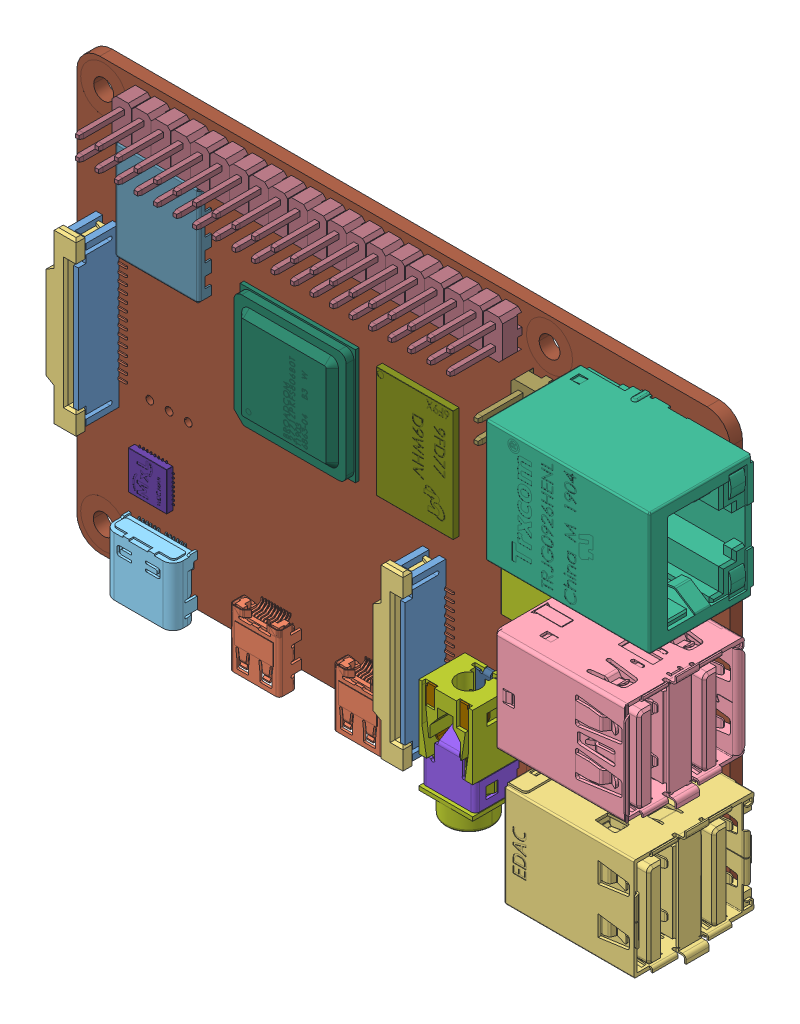
SolidWorks assembly Assembly Raspberry Pi 4 Model B step, configuration Default. Lengths in mm.
Overall size (89.07 58.45 20.84).
34 component instances, 25 part files, 0 mates.
Components (placement in the parent):
- Assembly Raspberry Pi 4 Model B step.STEP-1: Assembly Raspberry Pi 4 Model B step.STEP [Default] at origin size (89.07 58.45 20.84)
  - Display connector assembly.STEP-1: Display connector assembly.STEP [Default] at (-175.8005 -4.9769 88.3803) x (0 1 0) z (1 0 0) size (22.4 5.68 5.12)
    - 2.2 part 2 with combine.STEP-1: 2.2 part 2 with combine.STEP [Default] at (1.8587 0.0697 19.1) size (20.6 5.3 3)
    - 1.1 part 1 metal pin.STEP-1: 1.1 part 1 metal pin.STEP [Default] at (-5.0213 -2.5803 20.6021) x (0 0 1) z (-1 0 0) size (4.82 4.69 14.25)
    - 3.3 plastic.STEP-1: 3.3 plastic.STEP [Default] at (1.8587 1.7197 20.05) x (-1 0 0) z (0 1 0) size (22.4 3.9 5.18)
  - Display connector assembly-1.STEP-1: Display connector assembly-1.STEP [Default] at (-133.2905 -21.4369 88.3803) x (0 1 0) z (1 0 0) size (22.4 5.68 5.12)
    - 2.2 part 2 with combine.STEP-1: 2.2 part 2 with combine.STEP [Default] at (1.8587 0.0697 19.1) size (20.6 5.3 3)
    - 1.1 part 1 metal pin.STEP-1: 1.1 part 1 metal pin.STEP [Default] at (-5.0213 -2.5803 20.6021) x (0 0 1) z (-1 0 0) size (4.82 4.69 14.25)
    - 3.3 plastic.STEP-1: 3.3 plastic.STEP [Default] at (1.8587 1.7197 20.05) x (-1 0 0) z (0 1 0) size (22.4 3.9 5.18)
  - Card slot assembly.STEP-1: Card slot assembly.STEP [Default] at (-161.3453 3.4611 71.49) x (0 1 0) z (0 0 1) size (11.95 11.4 1.48)
    - card slot part 2 metal pin.STEP-1: card slot part 2 metal pin.STEP [Default] at (-3.5293 -7.6678 12.2938) x (0 -1 0) z (1 0 0) size (7.95 0.89 8.04)
    - sd card slot v1.STEP-1: sd card slot v1.STEP [Default] at (-18.1743 -9.7848 12.71) x (-1 0 0) z (0 0 -1) size (11.71 10.28 1.3)
    - part 3 v1.STEP-1: part 3 v1.STEP [Default] at (-6.4643 -9.3448 11.38) x (1 0 0) z (0 0 -1) size (11.95 11.4 1.45)
  - Microphone plug assembly.STEP-1: Microphone plug assembly.STEP [Default] at (-98.1635 -39.0194 79.6496) x (-1 0 0) z (0 1 0) size (7.23 7.55 15)
    - part 4 microphone plug.STEP-1: part 4 microphone plug.STEP [Default] at (7.027 9.1504 5.4512) size (7 6.8 15)
    - Microphone plug part 1.STEP-1: Microphone plug part 1.STEP [Default] at (7.027 11.4504 8.5512) x (-1 0 0) z (0 1 0) size (7.23 9.23 7.2)
    - part 2 microphon plug metal.STEP-1: part 2 microphon plug metal.STEP [Default] at (5.712 4.6004 12.1798) x (-1 0 0) z (0 1 0) size (6.87 8.22 7.3)
    - part 3 microphone plug.STEP-1: part 3 microphone plug.STEP [Default] at (7.042 6.6004 17.8712) x (-1 0 0) z (0 1 0) size (3.2 10.71 4.14)
  - 1.0 Plate raspberry Pi 4.STEP-1: 1.0 Plate raspberry Pi 4.STEP [Default] at (-116.6905 -3.1182 84.2) size (85 56 1.7)
  - 2.0. PIN HEADER  one.STEP-1: 2.0. PIN HEADER  one.STEP [Default] at (-97.6861 15.3918 88.3) size (5.08 5.08 11.8)
  - 3.0 PIN HEADER 20.STEP-1: 3.0 PIN HEADER 20.STEP [Default] at (-103.8305 21.3818 88.3) x (0 -1 0) z (0 0 1) size (5.08 50.8 11.8)
  - 4.0 metal plate..STEP-1: 4.0 metal plate..STEP [Default] at (-147.1905 11.3818 87.2) x (-1 0 0) z (0 0 1) size (11.01 13.01 1.6)
  - 5.0 CPU Broadcom.STEP-1: 5.0 CPU Broadcom.STEP [Default] at (-129.9505 1.4218 85.8) size (15 15 2.3)
  - 6.0 9FD77 D9WHV.STEP-1: 6.0 9FD77 D9WHV.STEP [Default] at (-114.4505 1.4218 85.8) size (10 14.5 0.8)
  - 7.0 MxL.STEP-1: 7.0 MxL.STEP [Default] at (-149.2005 -19.0782 85.8) size (5.48 5.48 0.9)
  - 8.0 Gigabit Ethernet Transceiver.STEP-1: 8.0 Gigabit Ethernet Transceiver.STEP [Default] at (-100.2005 6.9218 85.8) size (6.9 6.9 1.1)
  - 9.0 VLI PCIe USB 3.0 Controller.STEP-1: 9.0 VLI PCIe USB 3.0 Controller.STEP [Default] at (-99.2005 -7.0782 85.8) x (0 1 0) z (0 0 1) size (8.9 8.9 0.9)
  - 11.0 Female micro HDMI connector.STEP-1: 11.0 Female micro HDMI connector.STEP [Default] at (-133.2005 -25.4082 87.25) x (1 0 0) z (0 -1 0) size (6.5 3.51 7.5)
  - 11.0 Female micro HDMI connector.STEP-2: 11.0 Female micro HDMI connector.STEP [Default] at (-119.7005 -25.4082 87.25) x (1 0 0) z (0 -1 0) size (6.5 3.51 7.5)
  - 15.0   2x USB 2.0 PORT.STEP-1: 15.0   2x USB 2.0 PORT.STEP [Default] at (-87.9805 -22.0582 93.6) x (0 0 1) z (1 0 0) size (19.16 15.33 17.86)
  - 14.0  2x USB 3.0 PORT.STEP-1: 14.0  2x USB 3.0 PORT.STEP [Default] at (-88.0505 -4.0182 94.78) x (0 0 1) z (1 0 0) size (20.65 15.33 17.87)
  - 10.0 Female USB connector.STEP-1: 10.0 Female USB connector.STEP [Default] at (-147.9905 -24.6982 87.38) x (1 0 0) z (0 -1 0) size (8.94 3.96 7.9)
  - 12.0 Gigabit ethernet port raspberry.STEP-1: 12.0 Gigabit ethernet port raspberry.STEP [Default] at (-71.1905 14.6318 92.725) x (0 1 0) z (1 0 0) size (16.1 17.2 21.45)
  - 9.0 VLI PCIe USB 3.0 Controller v1.STEP-1: 9.0 VLI PCIe USB 3.0 Controller v1.STEP [Default] at (-99.1805 -7.0982 85.8092) size (8.9 8.9 0.9)
